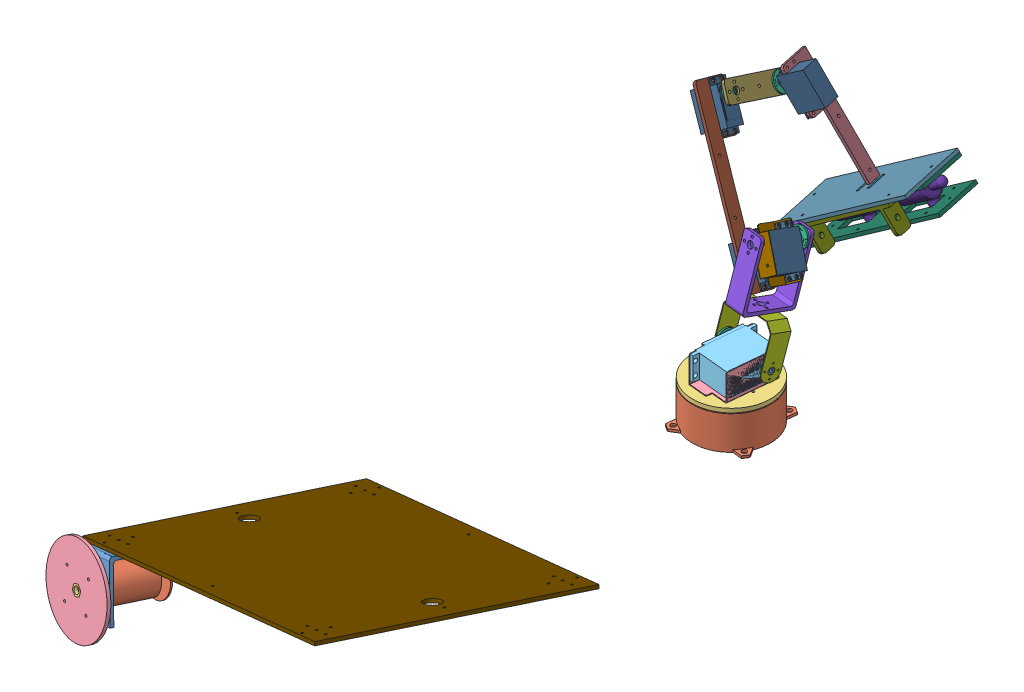
SolidWorks assembly arm 6 DOF + base, configuration Default. Lengths in mm.
Overall size (655.94 629.51 585.47).
31 component instances, 22 part files, 96 mates.
Components (placement in the parent):
- hs-422_sws-1: hs-422_sws [Default] at (6.6782 32.5822 43.0057) size (19.81 42.14 58.23)
- base arm-1: base arm [Default] at (19.6982 18.9554 48.4147) x (0.538087 0 -0.842889) z (0.842889 0 0.538087) size (118.01 42 118.01)
- arm base up-1: arm base up [Default] at (14.0386 54.8067 79.8215) x (-0.095518 0 0.995428) z (0 1 0) size (98 98 12)
- hs 755 bracket-1: hs 755 bracket [Default] at (-25.9831 89.2206 86.3781) x (-0.995428 0 -0.095518) z (0.095518 0 -0.995428) size (44 34 74)
- hitec hs 755-1: hitec hs 755 [Default] at (47.4118 123.9367 46.1035) x (0 1 0) z (-0.995428 0 -0.095518) size (29 74 56.99)
- servo bracket general-1: servo bracket general [Default] at (-13.2043 48.5068 70.6953) x (-0.068434 -0.697635 0.713177) z (0.995428 0 0.095518) size (24 24 6)
- u braket joint 1-2-1: u braket joint 1-2 [Default] at (37.4679 112.6177 16.8088) x (0.995428 0 0.095518) z (-0.091395 0.290649 0.952455) size (66 59 24)
- arm junc 2-1: arm junc 2 [Default] at (12.2198 164.6115 19.4632) x (-0.091395 0.290649 0.952455) z (0.995428 0 0.095518) size (64 79 24)
- bracket general hs 645-1: bracket general hs 645 [Default] at (13.6371 189.839 -27.8503) x (0.091395 -0.290649 -0.952455) z (0.555247 -0.779104 0.291029) size (34 24 57)
- hitec hs 645-1: hitec hs 645 [Default] at (11.2443 233.411 7.2013) x (-0.555247 0.779104 -0.291029) z (0.091395 -0.290649 -0.952455) size (53.34 19.56 42.35)
- servo bracket general-2: servo bracket general [Default] at (74.6343 177.2475 -16.1459) x (0.99569 0.011524 0.092027) z (-0.091395 0.290649 0.952455) size (24 24 6)
- hitec hs 645-2: hitec hs 645 [Default] at (-45.6075 189.6142 9.6339) x (-0.560486 0.798467 -0.219785) z (0.826648 0.555446 -0.090176) size (53.34 19.56 42.35)
- servo bracket general-3: servo bracket general [Default] at (15.4256 184.9176 48.3331) x (-0.045486 0.225683 0.973138) z (-0.826648 -0.555446 0.090176) size (24 24 6)
- juct c 2 joint-1: juct c 2 joint [Default] at (-100.7215 304.623 -41.4071) x (-0.560486 0.798467 -0.219785) z (0.826648 0.555446 -0.090176) size (196.25 35 4)
- hitec hs 645-3: hitec hs 645 [Default] at (-124.4264 301.8994 -21.2736) x (-0.560486 0.798467 -0.219785) z (0.826648 0.555446 -0.090176) size (53.34 19.56 42.35)
- servo bracket general-4: servo bracket general [Default] at (-36.7789 251.6358 -19.273) x (0.557382 -0.78621 0.266831) z (-0.826648 -0.555446 0.090176) size (24 24 6)
- arm junct hole 2-1: arm junct hole 2 [Default] at (-86.6987 318.9299 -62.3866) x (-0.558188 0.7891 -0.256412) z (0.826648 0.555446 -0.090176) size (24 80 4)
- hitec hs 645-4: hitec hs 645 [Default] at (-44.4921 337.7745 -93.6853) x (-0.54073 0.82844 0.14594) z (-0.826648 -0.555446 0.090176) size (53.34 19.56 42.35)
- servo bracket general-5: servo bracket general [Default] at (-58.8041 288.6132 -37.7716) x (-0.027131 0.199406 0.979541) z (0.826648 0.555446 -0.090176) size (24 24 6)
- juct c 1 joint-1: juct c 1 joint [Default] at (-56.6939 318.0564 -72.7805) x (-0.54073 0.82844 0.14594) z (-0.826648 -0.555446 0.090176) size (140.63 35 4)
- base effector-2: base effector [Default] at (20.5665 185.5464 -128.6083) x (0.826648 0.555446 -0.090176) z (-0.54073 0.82844 0.14594) size (180 80 4)
- base webcam fix-1: base webcam fix [Default] at (41.2738 193.4855 -124.3598) x (-0.826648 -0.555446 0.090176) z (0.54073 -0.82844 -0.14594) size (180 57 4)
- base GM-1: base GM [Default] at (69.6228 197.8899 -73.4273) x (0.826648 0.555446 -0.090176) z (-0.155767 0.07188 -0.985175) size (128 34 20)
- webcam sturdy-2: webcam sturdy [Default] at (45.6744 185.2482 -126.3907) x (-0.826648 -0.555446 0.090176) z (0.54073 -0.82844 -0.14594) size (79 27 33.5)
- webcam sturdy-3: webcam sturdy [Default] at (-26.244 136.9244 -118.5454) x (-0.826648 -0.555446 0.090176) z (0.54073 -0.82844 -0.14594) size (79 27 33.5)
- base webcam fix-4: base webcam fix [Default] at (27.5976 148.1585 -119.8676) x (0.826648 0.555446 -0.090176) z (0.54073 -0.82844 -0.14594) size (180 57 4)
- base-1: base [Default] at (-174.7105 -156.6771 314.6706) x (0.947844 0.262049 0.181442) z (-0.222856 0.951848 -0.210525) size (380 300 4)
- base junc motor-1: base junc motor [Default] at (-461.7309 -224.9666 341.1033) x (0.227873 -0.159109 -0.960603) z (0.947844 0.262049 0.181442) size (48 66 56)
- motor dc 1 NISCA-1: motor dc 1 NISCA [Default] at (-429.8392 -283.8945 385.8143) x (0.222856 -0.951848 0.210525) z (0.227873 -0.159109 -0.960603) size (54 48 92)
- shaft adapter motor-1: shaft adapter motor [Default] at (-435.2175 -255.9521 384.0743) x (0.960989 -0.12208 0.248185) z (-0.227873 0.159109 0.960603) size (12 13.86 17)
- wheel-1: wheel [Default] at (-513.8996 -260.5726 379.7079) x (-0.616252 -0.787391 -0.015767) z (-0.227873 0.159109 0.960603) size (100 100 4)
Mates (geometry in assembly coordinates):
- Coincident2: coincident anti-aligned: plane of hs-422_sws-1 through (26.4902 50.8067 43.0057) normal (0 1 0); plane of base arm-1 through (16.5842 50.8067 53.2927) normal (0 -1 0)
- Parallel4: parallel aligned: plane of hs-422_sws-1 through (26.4902 53.9729 43.0057) normal (0 1 0); plane of base arm-1 through (16.5842 53.8067 53.2927) normal (0 1 0)
- Concentric1: concentric aligned: cylinder of hs-422_sws-1 through (16.5842 34.7173 53.2927) axis (0 1 0) radius 2.8131; cylinder of base arm-1 through (16.5842 50.8067 53.2927) axis (0 1 0) radius 5
- Coincident4: coincident anti-aligned: plane of hs-422_sws-1 through (26.4902 50.8067 43.0057) normal (0 1 0); plane of arm base up-1 through (16.5842 50.8067 53.2927) normal (0 -1 0)
- Parallel5: parallel anti-aligned: plane of hs-422_sws-1 through (26.4902 53.9729 43.0057) normal (0 1 0); plane of arm base up-1 through (16.5842 54.8067 53.2927) normal (0 -1 0)
- Concentric2: concentric aligned: cylinder of hs-422_sws-1 through (16.5842 34.7173 53.2927) axis (0 1 0) radius 2.8131; cylinder of arm base up-1 through (16.5842 50.8067 53.2927) axis (0 1 0) radius 3
- Coincident6: coincident anti-aligned: plane of arm base up-1 through (16.5842 59.8067 53.2927) normal (0 1 0); plane of hs 755 bracket-1 through (49.9812 59.8067 19.3275) normal (0 -1 0)
- Concentric3: concentric aligned: cylinder of arm base up-1 through (16.5842 62.8067 53.2927) axis (0 -1 0) radius 4; cylinder of hs 755 bracket-1 through (16.5842 60.8067 53.2927) axis (0 -1 0) radius 4
- Concentric5: concentric anti-aligned: cylinder of arm base up-1 through (18.1125 54.8067 37.3659) axis (0 1 0) radius 1.5; cylinder of hs 755 bracket-1 through (18.1125 60.8067 37.3659) axis (0 -1 0) radius 4
- Concentric6: concentric anti-aligned: cylinder of arm base up-1 through (15.82 54.8067 61.2561) axis (0 1 0) radius 1.5; cylinder of hs 755 bracket-1 through (15.82 60.8067 61.2561) axis (0 -1 0) radius 1.5
- Concentric7: concentric anti-aligned: cylinder of arm base up-1 through (8.6208 54.8067 52.5286) axis (0 1 0) radius 1.5; cylinder of hs 755 bracket-1 through (8.6208 60.8067 52.5286) axis (0 -1 0) radius 1.5
- Coincident13: coincident anti-aligned: plane of hs 755 bracket-1 through (7.1778 60.8067 15.2202) normal (0.995428 0 0.095518); plane of hitec hs 755-1 through (4.6085 123.9367 41.9962) normal (-0.995428 0 -0.095518)
- Coincident14: coincident anti-aligned: plane of hs 755 bracket-1 through (7.1778 60.8067 15.2202) normal (0.995428 0 0.095518); plane of hitec hs 755-1 through (4.6085 123.9367 41.9962) normal (-0.995428 0 -0.095518)
- Concentric9: concentric aligned: cylinder of hs 755 bracket-1 through (6.8913 87.3067 18.2064) axis (-0.995428 0 -0.095518) radius 1.5; cylinder of hitec hs 755-1 through (10.873 87.3067 18.5885) axis (-0.995428 0 -0.095518) radius 2.5
- Concentric10: concentric aligned: cylinder of hs 755 bracket-1 through (6.8913 71.3067 18.2064) axis (-0.995428 0 -0.095518) radius 1.5; cylinder of hitec hs 755-1 through (10.873 71.3067 18.5885) axis (-0.995428 0 -0.095518) radius 2.5
- Concentric11: concentric aligned: cylinder of hs 755 bracket-1 through (0.396 71.3067 85.8955) axis (-0.995428 0 -0.095518) radius 1.5; cylinder of hitec hs 755-1 through (4.3777 71.3067 86.2776) axis (-0.995428 0 -0.095518) radius 2.5
- Concentric12: concentric aligned: cylinder of hs 755 bracket-1 through (0.396 87.3067 85.8955) axis (-0.995428 0 -0.095518) radius 1.5; cylinder of hitec hs 755-1 through (4.3777 87.3067 86.2776) axis (-0.995428 0 -0.095518) radius 2.5
- Parallel9: parallel aligned: plane of hs 755 bracket-1 through (6.1824 93.8067 15.1246) normal (0 1 0); plane of hitec hs 755-1 through (6.4614 93.8067 22.6859) normal (0 1 0)
- Coincident16: coincident anti-aligned: plane of hitec hs 755-1 through (-4.8202 78.8067 35.6676) normal (-0.995428 0 -0.095518); plane of servo bracket general-1 through (-4.8202 78.8067 35.6676) normal (0.995428 0 0.095518)
- Concentric13: concentric anti-aligned: cylinder of hitec hs 755-1 through (-8.8019 78.8067 35.2856) axis (0.995428 0 0.095518) radius 3; cylinder of servo bracket general-1 through (-4.8202 78.8067 35.6676) axis (-0.995428 0 -0.095518) radius 3
- Coincident17: coincident anti-aligned: plane of servo bracket general-1 through (-9.7973 78.8067 35.19) normal (-0.995428 0 -0.095518); plane of u braket joint 1-2-1 through (-9.8621 117.8613 35.865) normal (0.995428 0 0.095518)
- Concentric14: concentric anti-aligned: cylinder of servo bracket general-1 through (-10.7927 78.8067 35.0945) axis (0.995428 0 0.095518) radius 4; cylinder of u braket joint 1-2-1 through (-9.7973 78.8067 35.19) axis (-0.995428 0 -0.095518) radius 4
- Coincident18: coincident anti-aligned: plane of u braket joint 1-2-1 through (-1.2135 127.2655 33.8252) normal (0.027762 0.95683 -0.28932); plane of arm junc 2-1 through (34.9923 126.0877 33.4042) normal (-0.027762 -0.95683 0.28932)
- Concentric15: concentric anti-aligned: cylinder of u braket joint 1-2-1 through (23.7458 122.8208 24.9775) axis (0.027762 0.95683 -0.28932) radius 4; cylinder of arm junc 2-1 through (23.8846 127.605 23.5309) axis (-0.027762 -0.95683 0.28932) radius 4
- Concentric16: concentric anti-aligned: cylinder of u braket joint 1-2-1 through (24.4769 120.4957 17.3578) axis (0.027762 0.95683 -0.28932) radius 1; cylinder of arm junc 2-1 through (24.6157 125.2798 15.9112) axis (-0.027762 -0.95683 0.28932) radius 1.5
- Concentric17: concentric anti-aligned: cylinder of u braket joint 1-2-1 through (23.0146 125.146 32.5971) axis (0.027762 0.95683 -0.28932) radius 1; cylinder of arm junc 2-1 through (23.1534 129.9302 31.1505) axis (-0.027762 -0.95683 0.28932) radius 1.5
- Coincident19: coincident anti-aligned: plane of bracket general hs 645-1 through (37.7793 146.615 6.2326) normal (-0.091395 0.290649 0.952455); plane of hitec hs 645-1 through (13.8559 225.1057 -20.0151) normal (0.091395 -0.290649 -0.952455)
- Coincident20: coincident anti-aligned: plane of bracket general hs 645-1 through (37.7793 146.615 6.2326) normal (-0.091395 0.290649 0.952455); plane of hitec hs 645-1 through (13.8559 225.1057 -20.0151) normal (0.091395 -0.290649 -0.952455)
- Concentric18: concentric aligned: cylinder of bracket general hs 645-1 through (23.5444 198.232 -9.2678) axis (0.091395 -0.290649 -0.952455) radius 1.5; cylinder of hitec hs 645-1 through (23.3949 198.7072 -7.7106) axis (0.091395 -0.290649 -0.952455) radius 2.5019
- Concentric19: concentric aligned: cylinder of bracket general hs 645-1 through (15.1456 192.5887 -8.3516) axis (0.091395 -0.290649 -0.952455) radius 1.5; cylinder of hitec hs 645-1 through (14.9962 193.0639 -6.7944) axis (0.091395 -0.290649 -0.952455) radius 2.5019
- Concentric20: concentric aligned: cylinder of bracket general hs 645-1 through (50.3406 160.6325 4.7772) axis (0.091395 -0.290649 -0.952455) radius 1.5; cylinder of hitec hs 645-1 through (50.1912 161.1077 6.3345) axis (0.091395 -0.290649 -0.952455) radius 2.5019
- Concentric21: concentric aligned: cylinder of bracket general hs 645-1 through (41.9418 154.9892 5.6934) axis (0.091395 -0.290649 -0.952455) radius 1.5; cylinder of hitec hs 645-1 through (41.7924 155.4644 7.2507) axis (0.091395 -0.290649 -0.952455) radius 2.5019
- Coincident22: coincident anti-aligned: plane of hitec hs 645-1 through (28.0099 180.3284 -19.4601) normal (0.091395 -0.290649 -0.952455); plane of servo bracket general-2 through (28.0099 180.3284 -19.4601) normal (-0.091395 0.290649 0.952455)
- Concentric22: concentric anti-aligned: cylinder of hitec hs 645-1 through (28.0099 180.3284 -19.4601) axis (-0.091395 0.290649 0.952455) radius 2.9972; cylinder of servo bracket general-2 through (27.7357 181.2003 -16.6028) axis (0.091395 -0.290649 -0.952455) radius 3
- Lock1: lock: unknown of arm junc 2-1; unknown of servo bracket general-2
- Concentric23: concentric anti-aligned: cylinder of arm junc 2-1 through (28.1927 179.7471 -21.365) axis (0.091395 -0.290649 -0.952455) radius 4; cylinder of servo bracket general-2 through (28.2841 179.4564 -22.3175) axis (-0.091395 0.290649 0.952455) radius 4
- Coincident24: coincident anti-aligned: plane of hitec hs 645-2 through (14.1154 175.81 2.4022) normal (0.826648 0.555446 -0.090176); plane of servo bracket general-3 through (14.1154 175.81 2.4022) normal (-0.826648 -0.555446 0.090176)
- Concentric24: concentric anti-aligned: cylinder of hitec hs 645-2 through (14.1154 175.81 2.4022) axis (-0.826648 -0.555446 0.090176) radius 2.9972; cylinder of servo bracket general-3 through (11.6355 174.1437 2.6727) axis (0.826648 0.555446 -0.090176) radius 3
- Lock3: lock: unknown of bracket general hs 645-1; unknown of servo bracket general-3
- Concentric25: concentric aligned: cylinder of bracket general hs 645-1 through (16.5954 177.4764 2.1317) axis (-0.826648 -0.555446 0.090176) radius 4; cylinder of servo bracket general-3 through (16.5954 177.4764 2.1317) axis (-0.826648 -0.555446 0.090176) radius 4
- Coincident30: coincident anti-aligned: plane of hitec hs 645-2 through (18.1546 144.9277 20.3222) normal (-0.050076 0.232228 0.971372); plane of juct c 2 joint-1 through (-98.2624 310.7749 -25.3287) normal (0.050076 -0.232228 -0.971372)
- Coincident31: coincident anti-aligned: plane of hitec hs 645-2 through (-4.4812 177.1746 11.446) normal (-0.560486 0.798467 -0.219785); plane of juct c 2 joint-1 through (-3.6338 173.2444 -4.9931) normal (0.560486 -0.798467 0.219785)
- Coincident32: coincident anti-aligned: plane of hitec hs 645-2 through (-23.3508 204.569 7.206) normal (-0.826648 -0.555446 0.090176); plane of juct c 2 joint-1 through (-97.4149 306.8448 -41.7678) normal (0.826648 0.555446 -0.090176)
- Coincident33: coincident anti-aligned: plane of juct c 2 joint-1 through (-97.4149 306.8448 -41.7678) normal (0.826648 0.555446 -0.090176); plane of hitec hs 645-3 through (-102.1697 316.8543 -23.7015) normal (-0.826648 -0.555446 0.090176)
- Coincident34: coincident anti-aligned: plane of juct c 2 joint-1 through (-97.4149 306.8448 -41.7678) normal (0.826648 0.555446 -0.090176); plane of hitec hs 645-3 through (-102.1697 316.8543 -23.7015) normal (-0.826648 -0.555446 0.090176)
- Coincident35: coincident anti-aligned: plane of juct c 2 joint-1 through (-98.2624 310.7749 -25.3287) normal (0.050076 -0.232228 -0.971372); plane of hitec hs 645-3 through (-60.6644 257.2129 -10.5853) normal (-0.050076 0.232228 0.971372)
- Coincident36: coincident anti-aligned: plane of juct c 2 joint-1 through (-82.4527 285.5297 -35.9006) normal (0.560486 -0.798467 0.219785); plane of hitec hs 645-3 through (-83.3002 289.4598 -19.4616) normal (-0.560486 0.798467 -0.219785)
- Coincident37: coincident anti-aligned: plane of hitec hs 645-3 through (-64.7035 288.0953 -28.5053) normal (0.826648 0.555446 -0.090176); plane of servo bracket general-4 through (-64.7035 288.0953 -28.5053) normal (-0.826648 -0.555446 0.090176)
- Concentric26: concentric anti-aligned: cylinder of hitec hs 645-3 through (-64.7035 288.0953 -28.5053) axis (-0.826648 -0.555446 0.090176) radius 2.9972; cylinder of servo bracket general-4 through (-67.1835 286.4289 -28.2348) axis (0.826648 0.555446 -0.090176) radius 3
- Lock4: lock: unknown of servo bracket general-4; unknown of arm junct hole 2-1
- Concentric27: concentric anti-aligned: cylinder of servo bracket general-4 through (-62.2236 289.7616 -28.7759) axis (-0.826648 -0.555446 0.090176) radius 4; cylinder of arm junct hole 2-1 through (-63.0502 289.2062 -28.6857) axis (0.826648 0.555446 -0.090176) radius 4
- Concentric28: concentric anti-aligned: cylinder of hitec hs 645-4 through (-54.2441 277.7529 -83.1027) axis (0.826648 0.555446 -0.090176) radius 2.9972; cylinder of servo bracket general-5 through (-51.6195 279.5165 -83.389) axis (-0.826648 -0.555446 0.090176) radius 3
- Coincident40: coincident anti-aligned: plane of hitec hs 645-4 through (-51.6195 279.5165 -83.389) normal (-0.826648 -0.555446 0.090176); plane of servo bracket general-5 through (-51.6195 279.5165 -83.389) normal (0.826648 0.555446 -0.090176)
- Lock5: lock: unknown of arm junct hole 2-1; unknown of servo bracket general-5
- Concentric29: concentric aligned: cylinder of arm junct hole 2-1 through (-59.0593 274.5175 -82.5774) axis (0.826648 0.555446 -0.090176) radius 4; cylinder of servo bracket general-5 through (-56.5794 276.1838 -82.8479) axis (0.826648 0.555446 -0.090176) radius 4
- Coincident42: coincident anti-aligned: plane of hitec hs 645-4 through (-26.3639 261.4784 -98.8822) normal (0.54073 -0.82844 -0.14594); plane of juct c 1 joint-1 through (-23.7277 260.262 -82.2096) normal (-0.54073 0.82844 0.14594)
- Coincident43: coincident anti-aligned: plane of hitec hs 645-4 through (-48.2018 294.9358 -92.9883) normal (-0.54073 0.82844 0.14594); plane of juct c 1 joint-1 through (-45.5657 293.7193 -76.3157) normal (0.54073 -0.82844 -0.14594)
- Coincident44: coincident anti-aligned: plane of hitec hs 645-4 through (-26.3639 261.4784 -98.8822) normal (-0.155767 0.07188 -0.985175); plane of juct c 1 joint-1 through (-62.6366 317.0511 -89.0924) normal (0.155767 -0.07188 0.985175)
- Coincident45: coincident anti-aligned: plane of hitec hs 645-4 through (-66.7488 322.8196 -91.2574) normal (0.826648 0.555446 -0.090176); plane of juct c 1 joint-1 through (-60.0005 315.8346 -72.4198) normal (-0.826648 -0.555446 0.090176)
- Coincident54: coincident anti-aligned: plane of juct c 1 joint-1 through (-60.0005 315.8346 -72.4198) normal (-0.826648 -0.555446 0.090176); plane of base effector-2 through (21.3197 185.8553 -127.5709) normal (0.826648 0.555446 -0.090176)
- Coincident55: coincident anti-aligned: plane of juct c 1 joint-1 through (-62.6366 317.0511 -89.0924) normal (0.155767 -0.07188 0.985175); plane of base effector-2 through (23.7185 184.7483 -112.3992) normal (-0.155767 0.07188 -0.985175)
- Coincident57: coincident aligned: plane of juct c 1 joint-1 through (26.3547 183.5319 -95.7266) normal (0.54073 -0.82844 -0.14594); plane of base effector-2 through (20.5665 185.5464 -128.6083) normal (0.54073 -0.82844 -0.14594)
- Coincident58: coincident anti-aligned: plane of base effector-2 through (20.5665 185.5464 -128.6083) normal (0.54073 -0.82844 -0.14594); plane of base webcam fix-1 through (39.1109 196.7992 -123.776) normal (-0.54073 0.82844 0.14594)
- Concentric31: concentric aligned: cylinder of base effector-2 through (-43.9978 145.2333 -111.5795) axis (0.54073 -0.82844 -0.14594) radius 1.5; cylinder of base webcam fix-1 through (-41.8348 141.9195 -112.1632) axis (0.54073 -0.82844 -0.14594) radius 1.5
- Concentric32: concentric aligned: cylinder of base effector-2 through (88.266 234.1047 -126.0076) axis (0.54073 -0.82844 -0.14594) radius 1.5; cylinder of base webcam fix-1 through (90.4289 230.7909 -126.5914) axis (0.54073 -0.82844 -0.14594) radius 1.5
- Coincident59: coincident anti-aligned: plane of base effector-2 through (20.5665 185.5464 -128.6083) normal (0.54073 -0.82844 -0.14594); plane of base GM-1 through (-15.4353 154.0969 -83.4748) normal (-0.54073 0.82844 0.14594)
- Concentric33: concentric aligned: cylinder of base effector-2 through (-20.1738 153.9146 -72.5884) axis (0.54073 -0.82844 -0.14594) radius 1.5; cylinder of base GM-1 through (-18.0109 150.6008 -73.1721) axis (0.54073 -0.82844 -0.14594) radius 1.5
- Concentric34: concentric aligned: cylinder of base effector-2 through (77.3707 219.4573 -83.2292) axis (0.54073 -0.82844 -0.14594) radius 1.5; cylinder of base GM-1 through (79.5336 216.1435 -83.8129) axis (0.54073 -0.82844 -0.14594) radius 1.5
- Tangent3: tangent anti-aligned: plane of base effector-2 through (20.5665 185.5464 -128.6083) normal (0.54073 -0.82844 -0.14594); cylinder of webcam sturdy-2 through (84.7839 211.5269 -130.657) axis (0.826648 0.555446 -0.090176) radius 13.5
- Coincident63: coincident anti-aligned: plane of base webcam fix-1 through (42.0508 198.7746 -124.0967) normal (0.826648 0.555446 -0.090176); plane of webcam sturdy-2 through (49.238 187.6427 -126.7795) normal (-0.826648 -0.555446 0.090176)
- Coincident64: coincident anti-aligned: plane of base webcam fix-1 through (77.5967 222.6588 -127.9743) normal (-0.826648 -0.555446 0.090176); plane of webcam sturdy-2 through (84.7839 211.5269 -130.657) normal (0.826648 0.555446 -0.090176)
- Tangent4: tangent anti-aligned: plane of base webcam fix-1 through (41.1011 195.8808 -111.1887) normal (-0.155767 0.07188 -0.985175); cylinder of webcam sturdy-2 through (84.7839 211.5269 -130.657) axis (0.826648 0.555446 -0.090176) radius 13.5
- Tangent13: tangent anti-aligned: plane of base effector-2 through (20.5665 185.5464 -128.6083) normal (0.54073 -0.82844 -0.14594); cylinder of webcam sturdy-3 through (12.8654 163.203 -122.8117) axis (0.826648 0.555446 -0.090176) radius 13.5
- Coincident69: coincident anti-aligned: plane of base webcam fix-1 through (-29.8676 150.4508 -116.2514) normal (0.826648 0.555446 -0.090176); plane of webcam sturdy-3 through (-22.6804 139.3188 -118.9342) normal (-0.826648 -0.555446 0.090176)
- Coincident70: coincident anti-aligned: plane of base webcam fix-1 through (5.6782 174.335 -120.129) normal (-0.826648 -0.555446 0.090176); plane of webcam sturdy-3 through (12.8654 163.203 -122.8117) normal (0.826648 0.555446 -0.090176)
- Tangent14: tangent anti-aligned: plane of base webcam fix-1 through (41.1011 195.8808 -111.1887) normal (-0.155767 0.07188 -0.985175); cylinder of webcam sturdy-3 through (12.8654 163.203 -122.8117) axis (0.826648 0.555446 -0.090176) radius 13.5
- Parallel17: parallel anti-aligned: plane of base webcam fix-1 through (41.2738 193.4855 -124.3598) normal (0.54073 -0.82844 -0.14594); plane of base webcam fix-4 through (25.4347 151.4722 -119.2838) normal (-0.54073 0.82844 0.14594)
- Concentric37: concentric aligned: cylinder of base webcam fix-1 through (-33.9462 150.9275 -134.0693) axis (0.54073 -0.82844 -0.14594) radius 1.5; cylinder of base webcam fix-4 through (-17.9947 126.4885 -138.3745) axis (0.54073 -0.82844 -0.14594) radius 1.5
- Concentric38: concentric aligned: cylinder of base webcam fix-1 through (75.998 224.8019 -146.0627) axis (0.54073 -0.82844 -0.14594) radius 1.5; cylinder of base webcam fix-4 through (91.9496 200.3629 -150.3679) axis (0.54073 -0.82844 -0.14594) radius 1.5
- Coincident74: coincident anti-aligned: plane of webcam sturdy-3 through (12.8654 163.203 -122.8117) normal (0.826648 0.555446 -0.090176); plane of base webcam fix-4 through (22.4948 149.4968 -118.9631) normal (-0.826648 -0.555446 0.090176)
- Coincident75: coincident anti-aligned: plane of webcam sturdy-3 through (-22.6804 139.3188 -118.9342) normal (-0.826648 -0.555446 0.090176); plane of base webcam fix-4 through (-13.0511 125.6126 -115.0855) normal (0.826648 0.555446 -0.090176)
- Coincident77: coincident anti-aligned: plane of webcam sturdy-2 through (84.7839 211.5269 -130.657) normal (0.826648 0.555446 -0.090176); plane of base webcam fix-4 through (94.4132 197.8207 -126.8084) normal (-0.826648 -0.555446 0.090176)
- Coincident81: coincident aligned: plane of webcam sturdy-2 through (87.332 189.4036 -132.6741) normal (0.54073 -0.82844 -0.14594); plane of base webcam fix-4 through (27.5976 148.1585 -119.8676) normal (0.54073 -0.82844 -0.14594)
- Coincident82: coincident aligned: plane of webcam sturdy-3 through (15.4135 141.0798 -124.8288) normal (0.54073 -0.82844 -0.14594); plane of base webcam fix-4 through (27.5976 148.1585 -119.8676) normal (0.54073 -0.82844 -0.14594)
- Coincident87: coincident anti-aligned: plane of base junc motor-1 through (-481.0277 -284.6566 373.7976) normal (0.227873 -0.159109 -0.960603); plane of motor dc 1 NISCA-1 through (-461.3966 -247.8119 372.3517) normal (-0.227873 0.159109 0.960603)
- Concentric39: concentric aligned: cylinder of base junc motor-1 through (-462.3081 -247.1755 376.1941) axis (0.227873 -0.159109 -0.960603) radius 9.5; cylinder of motor dc 1 NISCA-1 through (-462.3081 -247.1755 376.1941) axis (0.227873 -0.159109 -0.960603) radius 9
- Concentric40: concentric anti-aligned: cylinder of base junc motor-1 through (-457.1824 -269.068 381.0362) axis (0.227873 -0.159109 -0.960603) radius 1; cylinder of motor dc 1 NISCA-1 through (-455.8152 -270.0227 375.2726) axis (-0.227873 0.159109 0.960603) radius 1.5
- Concentric41: concentric anti-aligned: cylinder of base junc motor-1 through (-467.4338 -225.283 371.3521) axis (0.227873 -0.159109 -0.960603) radius 1; cylinder of motor dc 1 NISCA-1 through (-466.0666 -226.2377 365.5885) axis (-0.227873 0.159109 0.960603) radius 1.5
- Coincident88: coincident anti-aligned: plane of motor dc 1 NISCA-1 through (-430.7507 -283.2581 389.6567) normal (-0.227873 0.159109 0.960603); plane of shaft adapter motor-1 through (-462.3081 -247.1755 376.1941) normal (0.227873 -0.159109 -0.960603)
- Concentric42: concentric aligned: cylinder of motor dc 1 NISCA-1 through (-465.2705 -245.1071 388.682) axis (0.227873 -0.159109 -0.960603) radius 2.5; cylinder of shaft adapter motor-1 through (-465.2705 -245.1071 388.682) axis (0.227873 -0.159109 -0.960603) radius 2.5
- Coincident93: coincident anti-aligned: plane of shaft adapter motor-1 through (-471.4049 -240.3444 390.602) normal (-0.960989 0.12208 -0.248185); plane of wheel-1 through (-470.4934 -240.9809 386.7596) normal (0.960989 -0.12208 0.248185)
- Coincident94: coincident anti-aligned: plane of shaft adapter motor-1 through (-467.268 -251.2581 393.391) normal (0.344738 -0.909471 0.232418); plane of wheel-1 through (-466.3565 -251.8945 389.5486) normal (-0.344738 0.909471 -0.232418)
- Coincident95: coincident aligned: plane of shaft adapter motor-1 through (-439.0914 -253.2472 400.4045) normal (-0.227873 0.159109 0.960603); plane of wheel-1 through (-466.182 -244.4707 392.5244) normal (-0.227873 0.159109 0.960603)
- Coincident96: coincident anti-aligned: plane of base-1 through (-174.7105 -156.6771 314.6706) normal (0.222856 -0.951848 0.210525); plane of base junc motor-1 through (-485.7098 -228.8354 317.6365) normal (-0.222856 0.951848 -0.210525)
- Concentric50: concentric aligned: cylinder of base-1 through (-478.8367 -218.4392 338.3652) axis (0.222856 -0.951848 0.210525) radius 1.5; cylinder of base junc motor-1 through (-477.9453 -222.2466 339.2073) axis (0.222856 -0.951848 0.210525) radius 1.5
- Concentric51: concentric aligned: cylinder of base-1 through (-450.4014 -210.5778 343.8084) axis (0.222856 -0.951848 0.210525) radius 1.5; cylinder of base junc motor-1 through (-449.51 -214.3851 344.6505) axis (0.222856 -0.951848 0.210525) radius 1.5
